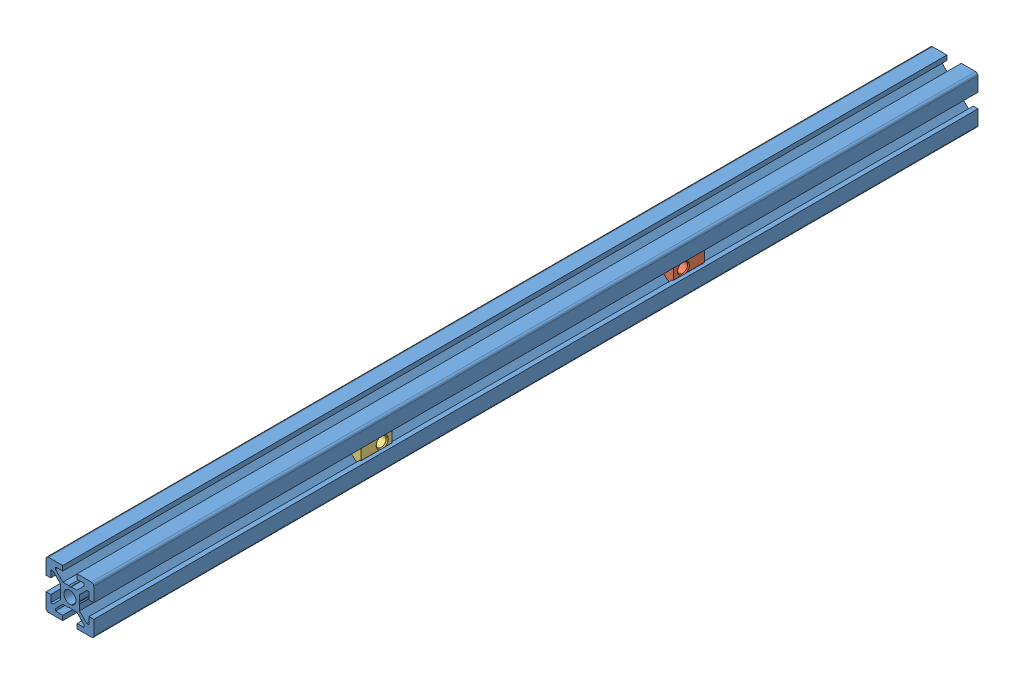
SolidWorks assembly HFSB5-2020-370-TPW, configuration Default. Lengths in mm.
Overall size (20 20 370).
3 component instances, 3 part files, 4 mates.
Components (placement in the parent):
- HFSB5-2020-370-TPW (1)-1: HFSB5-2020-370-TPW (1) [Default] at (179.4245 40.4288 32.2963) size (20 20 370)
- 2020 Drop-in T-nut, M5-1-1: 2020 Drop-in T-nut, M5-1 [Default] at (188.0245 39.8788 -223.8496) x (0 1 0) z (0 0 -1) size (7.7 4.3 13)
- 2020 Drop-in T-nut, M5-2-1: 2020 Drop-in T-nut, M5-2 [Default] at (188.0245 39.8788 -81.775) x (0 -1 0) z (0 0 1) size (7.7 4.3 13)
Mates (geometry in assembly coordinates):
- Coincident1: coincident anti-aligned: plane of HFSB5-2020-370-TPW (1)-1 through (187.4245 46.4288 -337.7037) normal (-1 0 0); plane of 2020 Drop-in T-nut, M5 (20)-1 through (187.4245 42.5788 -223.8496) normal (1 0 0)
- Coincident2: coincident anti-aligned: plane of HFSB5-2020-370-TPW (1)-1 through (187.4245 46.4288 -337.7037) normal (-1 0 0); plane of 2020 Drop-in T-nut, M5 (21)-1 through (187.4245 43.0288 -81.775) normal (1 0 0)
- Coincident3: coincident anti-aligned: plane of HFSB5-2020-370-TPW (1)-1 through (189.4245 37.4288 -337.7037) normal (0 1 0); plane of 2020 Drop-in T-nut, M5 (20)-1 through (187.6745 37.4288 -223.8496) normal (0 -1 0)
- Coincident4: coincident anti-aligned: plane of HFSB5-2020-370-TPW (1)-1 through (189.4245 37.4288 -337.7037) normal (0 1 0); plane of 2020 Drop-in T-nut, M5 (21)-1 through (187.7745 37.4288 -81.775) normal (0 -1 0)
